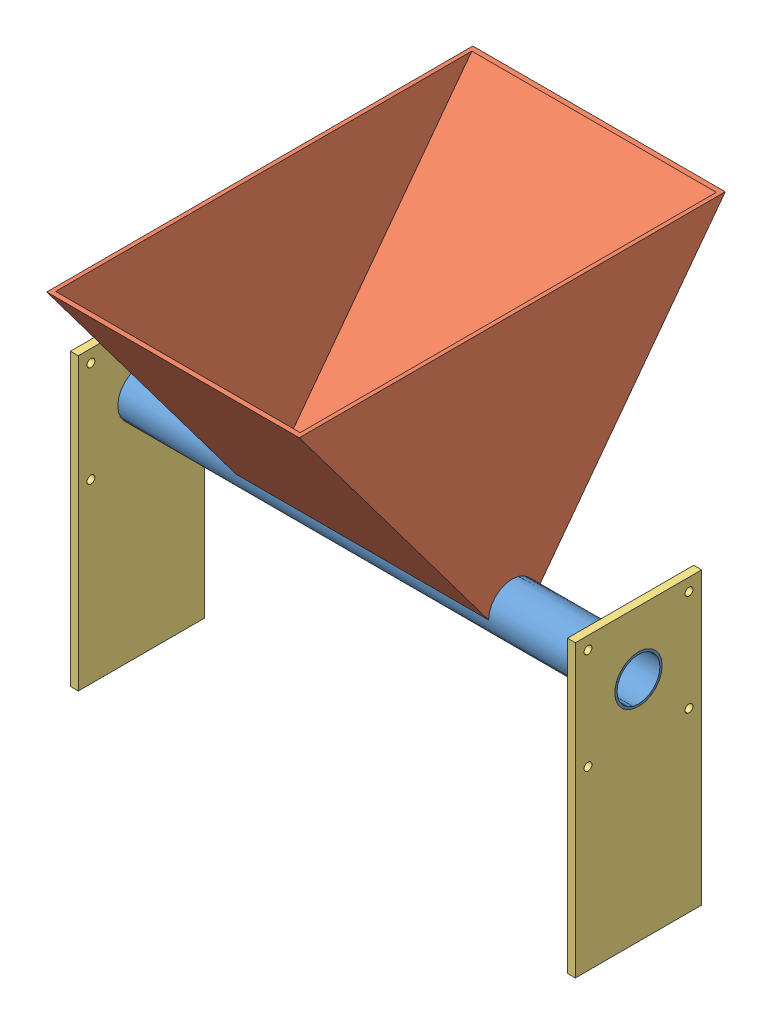
SolidWorks assembly Hopper Assm, configuration Default. Lengths in mm.
Overall size (203.2 193.04 171.45).
4 component instances, 3 part files, 9 mates.
Components (placement in the parent):
- Hopper barrel-1: Hopper barrel [Default<As Machined>] at (-105.2323 4.7582 -1.3159) size (203.2 19.05 19.05)
- hopper-1: hopper [Default] at (-54.4323 4.7582 -1.3159) size (101.6 101.6 171.45)
- hopper flange long-3: hopper flange long [Default] at (97.9677 -20.6418 -26.7159) x (0 0 1) z (-1 0 0) size (50.8 116.84 3.17)
- hopper flange long-2: hopper flange long [Default] at (-105.2323 -20.6418 24.0841) x (0 0 -1) z (1 0 0) size (50.8 116.84 3.17)
Mates (geometry in assembly coordinates):
- Coincident1: coincident anti-aligned: circle of Hopper barrel-1; circle of hopper-1
- Coincident2: coincident anti-aligned: line of Hopper barrel-1 through (-54.4323 4.7582 8.2091) axis (1 0 0); line of hopper-1 through (47.1677 4.7582 8.2091) axis (-1 0 0)
- Concentric1: concentric anti-aligned: cylinder of Hopper barrel-1 through (-105.2323 4.7582 -1.3159) axis (-1 0 0) radius 8.636; cylinder of hopper flange long-3 through (94.7927 4.7582 -1.3159) axis (1 0 0) radius 9.525
- Coincident3: coincident aligned: circle of Hopper barrel-1; circle of hopper flange long-3
- Concentric2: concentric aligned: cylinder of Hopper barrel-1 through (-105.2323 4.7582 -1.3159) axis (-1 0 0) radius 9.525; cylinder of hopper flange long-2 through (-102.0573 4.7582 -1.3159) axis (-1 0 0) radius 9.525
- Parallel1: parallel aligned: plane of hopper flange long-3 through (94.7927 30.1582 -26.7159) normal (0 1 0); plane of hopper flange long-2 through (-102.0573 30.1582 24.0841) normal (0 1 0)
- Coincident7: coincident aligned: plane of Hopper barrel-1 through (-105.2323 4.7582 -9.9519) normal (-1 0 0); plane of hopper flange long-2 through (-105.2323 30.1582 24.0841) normal (-1 0 0)
- Parallel3: parallel anti-aligned: line of hopper flange long-3 through (94.7927 30.1582 24.0841) axis (0 0 -1); line of hopper flange long-2 through (-105.2323 30.1582 -26.7159) axis (0 0 1)
- Parallel4: parallel: line of hopper flange long-2 through (-105.2323 30.1582 -26.7159) axis (0 0 1); plane of assembly
